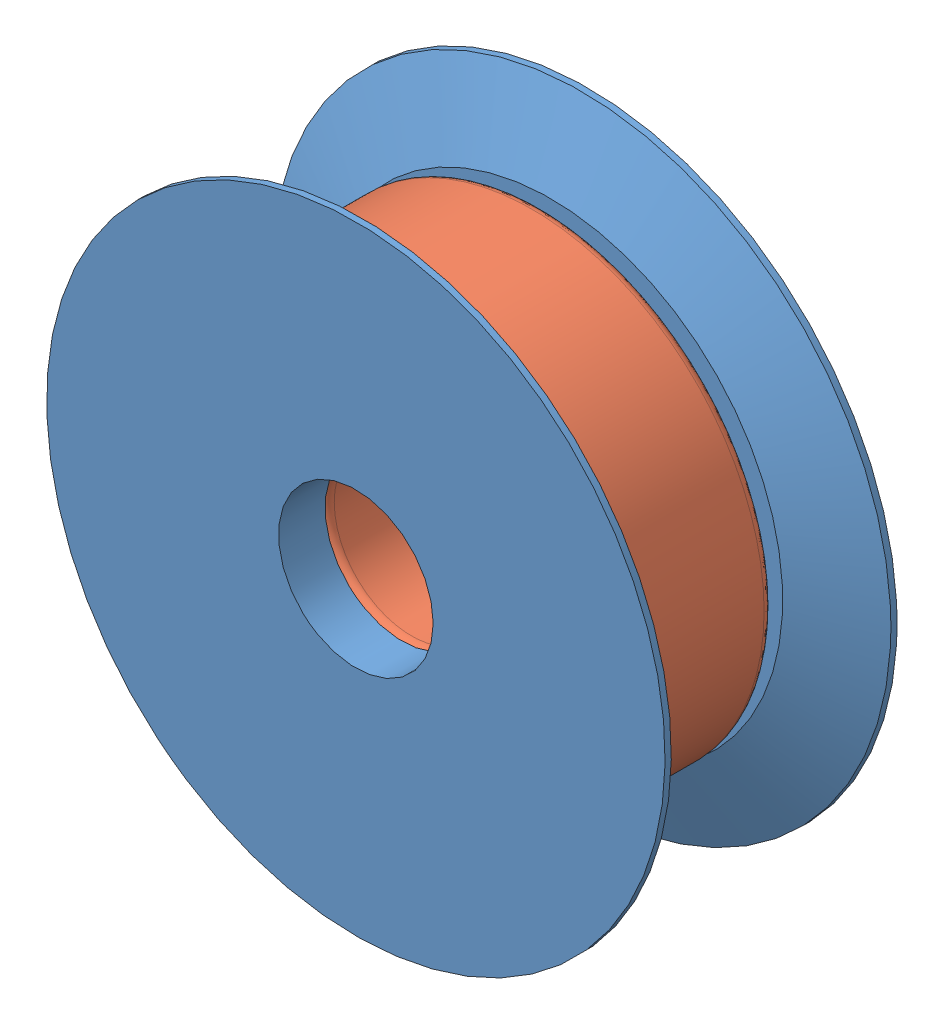
SolidWorks assembly Bearing with washers, configuration По умолчанию. Lengths in mm.
Overall size (50.37 50.37 15).
3 component instances, 2 part files, 4 mates.
Components (placement in the parent):
- Bearing washer-1: Bearing washer [По умолчанию] at (-0.3962 2.3527 0) size (36 36 3)
- Bearing washer-2: Bearing washer [По умолчанию] at (-0.3962 2.3527 15) x (-0.59663 -0.802517 0) z (0 0 -1) size (36 36 3)
- Radial Ball Bearing_68_DIN-1: Radial Ball Bearing_68_DIN [DIN 625 - 6200 - 8,SI,NC,8_68] at (-0.3962 2.3527 7.5) x (0 0 1) z (-1 0 0) size (9 30 30)
Mates (geometry in assembly coordinates):
- Концентричный1: concentric anti-aligned: cylinder of Bearing washer-1 through (-0.3962 2.3527 2.4) axis (0 0 -1) radius 5; cylinder of Radial Ball Bearing_68_DIN-1 through (-0.3962 2.3527 -13.1375) axis (0 0 1) radius 5
- Концентричный2: concentric aligned: cylinder of Bearing washer-2 through (-0.3962 2.3527 12.6) axis (0 0 1) radius 5; cylinder of Radial Ball Bearing_68_DIN-1 through (-0.3962 2.3527 -13.1375) axis (0 0 1) radius 5
- Совпадение1: coincident anti-aligned: plane of Bearing washer-1 through (-0.3962 2.3527 3) normal (0 0 1); plane of Radial Ball Bearing_68_DIN-1 through (-0.3962 10.3527 3) normal (0 0 -1)
- Совпадение2: coincident anti-aligned: plane of Bearing washer-2 through (-0.3962 2.3527 12) normal (0 0 -1); plane of Radial Ball Bearing_68_DIN-1 through (-0.3962 7.9527 12) normal (0 0 1)
